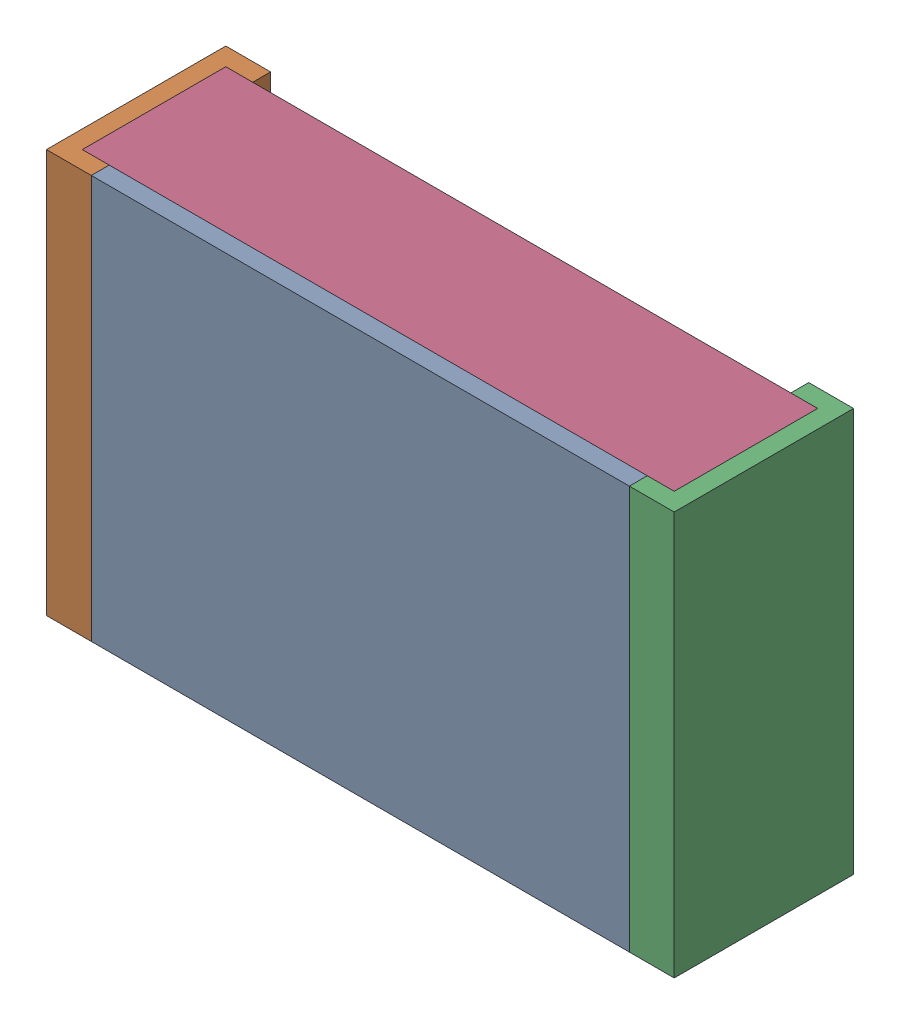
SolidWorks assembly R74, configuration По умолчанию. Lengths in mm.
Overall size (2.1 1.35 0.6).
5 component instances, 3 part files, 0 mates.
Components (placement in the parent):
- RESC2012X06N.step-1: RESC2012X06N.step [По умолчанию] at origin size (2.1 1.35 0.6)
  - RESC2012X06N.step-Part-1-1: RESC2012X06N.step-Part-1 [По умолчанию] at (-0.9 -0.675 0.54) size (1.8 1.35 0.06)
  - RESC2012X06N.step-Part-2-1: RESC2012X06N.step-Part-2 [По умолчанию] at (-1.05 -0.675 0) size (0.15 1.35 0.6)
  - RESC2012X06N.step-Part-2-2: RESC2012X06N.step-Part-2 [По умолчанию] at (1.05 0.675 0) x (-1 0 0) z (0 0 1) size (0.15 1.35 0.6)
  - RESC2012X06N.step-Part-3-1: RESC2012X06N.step-Part-3 [По умолчанию] at (-1.05 -0.675 0) size (1.98 1.35 0.48)
